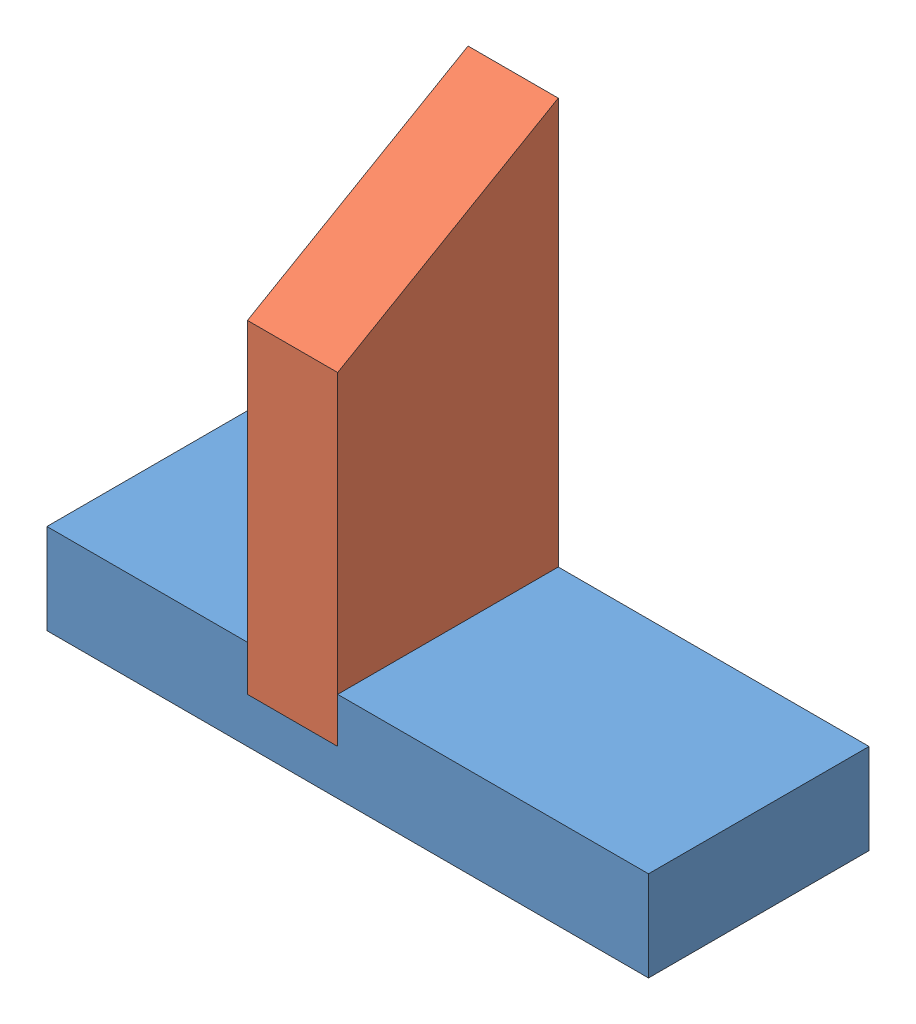
SolidWorks assembly HOUSED JOINT 1, configuration Default. Lengths in mm.
Overall size (120 99 44).
2 component instances, 2 part files, 3 mates.
Components (placement in the parent):
- BASE PIECE-1: BASE PIECE [Default] at (31.2716 -22.4448 -1.253) size (120 18 44)
- UPRIGHT-1: UPRIGHT [Default] at (-48.7284 -13.4448 -45.253) size (18 90 44)
Mates (geometry in assembly coordinates):
- Coincident1: coincident anti-aligned: line of BASE PIECE-1 through (-48.7284 -13.4448 -1.253) axis (1 0 0); line of UPRIGHT-1 through (-30.7284 -13.4448 -1.253) axis (-1 0 0)
- Coincident2: coincident anti-aligned: plane of BASE PIECE-1 through (-48.7284 -4.4448 -45.254) normal (1 0 0); plane of UPRIGHT-1 through (-48.7284 -13.4448 -45.253) normal (-1 0 0)
- Coincident3: coincident anti-aligned: plane of BASE PIECE-1 through (-48.7284 -13.4448 -45.254) normal (0 1 0); plane of UPRIGHT-1 through (-30.7284 -13.4448 -1.253) normal (0 -1 0)
